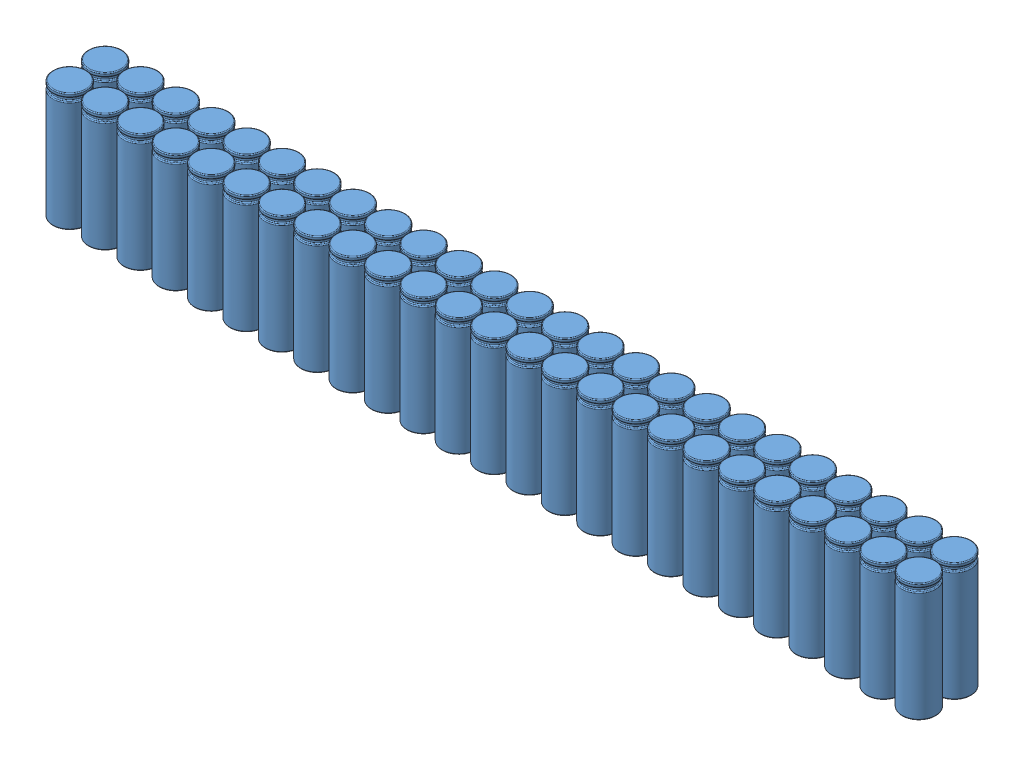
SolidWorks assembly 25x2, configuration Default. Lengths in mm.
Overall size (486.5 65.2 38).
50 component instances, 1 part files, 1 mates.
Components (placement in the parent):
- 18650 NN-1: 18650 NN [Default] at origin size (18.5 65.2 18.5)
- 18650 NN-2: 18650 NN [Default] at (0 0 -19.5) size (18.5 65.2 18.5)
- 18650 NN-3: 18650 NN [Default] at (19.5 0 0) size (18.5 65.2 18.5)
- 18650 NN-4: 18650 NN [Default] at (19.5 0 -19.5) size (18.5 65.2 18.5)
- 18650 NN-5: 18650 NN [Default] at (39 0 0) size (18.5 65.2 18.5)
- 18650 NN-6: 18650 NN [Default] at (39 0 -19.5) size (18.5 65.2 18.5)
- 18650 NN-7: 18650 NN [Default] at (58.5 0 0) size (18.5 65.2 18.5)
- 18650 NN-8: 18650 NN [Default] at (58.5 0 -19.5) size (18.5 65.2 18.5)
- 18650 NN-9: 18650 NN [Default] at (78 0 0) size (18.5 65.2 18.5)
- 18650 NN-10: 18650 NN [Default] at (78 0 -19.5) size (18.5 65.2 18.5)
- 18650 NN-11: 18650 NN [Default] at (97.5 0 0) size (18.5 65.2 18.5)
- 18650 NN-12: 18650 NN [Default] at (97.5 0 -19.5) size (18.5 65.2 18.5)
- 18650 NN-13: 18650 NN [Default] at (117 0 0) size (18.5 65.2 18.5)
- 18650 NN-14: 18650 NN [Default] at (117 0 -19.5) size (18.5 65.2 18.5)
- 18650 NN-15: 18650 NN [Default] at (136.5 0 0) size (18.5 65.2 18.5)
- 18650 NN-16: 18650 NN [Default] at (136.5 0 -19.5) size (18.5 65.2 18.5)
- 18650 NN-17: 18650 NN [Default] at (156 0 0) size (18.5 65.2 18.5)
- 18650 NN-18: 18650 NN [Default] at (156 0 -19.5) size (18.5 65.2 18.5)
- 18650 NN-19: 18650 NN [Default] at (175.5 0 0) size (18.5 65.2 18.5)
- 18650 NN-20: 18650 NN [Default] at (175.5 0 -19.5) size (18.5 65.2 18.5)
- 18650 NN-21: 18650 NN [Default] at (195 0 0) size (18.5 65.2 18.5)
- 18650 NN-22: 18650 NN [Default] at (195 0 -19.5) size (18.5 65.2 18.5)
- 18650 NN-23: 18650 NN [Default] at (214.5 0 0) size (18.5 65.2 18.5)
- 18650 NN-24: 18650 NN [Default] at (214.5 0 -19.5) size (18.5 65.2 18.5)
- 18650 NN-25: 18650 NN [Default] at (234 0 0) size (18.5 65.2 18.5)
- 18650 NN-26: 18650 NN [Default] at (234 0 -19.5) size (18.5 65.2 18.5)
- 18650 NN-27: 18650 NN [Default] at (253.5 0 0) size (18.5 65.2 18.5)
- 18650 NN-28: 18650 NN [Default] at (253.5 0 -19.5) size (18.5 65.2 18.5)
- 18650 NN-29: 18650 NN [Default] at (273 0 0) size (18.5 65.2 18.5)
- 18650 NN-30: 18650 NN [Default] at (273 0 -19.5) size (18.5 65.2 18.5)
- 18650 NN-31: 18650 NN [Default] at (292.5 0 0) size (18.5 65.2 18.5)
- 18650 NN-32: 18650 NN [Default] at (292.5 0 -19.5) size (18.5 65.2 18.5)
- 18650 NN-33: 18650 NN [Default] at (312 0 0) size (18.5 65.2 18.5)
- 18650 NN-34: 18650 NN [Default] at (312 0 -19.5) size (18.5 65.2 18.5)
- 18650 NN-35: 18650 NN [Default] at (331.5 0 0) size (18.5 65.2 18.5)
- 18650 NN-36: 18650 NN [Default] at (331.5 0 -19.5) size (18.5 65.2 18.5)
- 18650 NN-37: 18650 NN [Default] at (351 0 0) size (18.5 65.2 18.5)
- 18650 NN-38: 18650 NN [Default] at (351 0 -19.5) size (18.5 65.2 18.5)
- 18650 NN-39: 18650 NN [Default] at (370.5 0 0) size (18.5 65.2 18.5)
- 18650 NN-40: 18650 NN [Default] at (370.5 0 -19.5) size (18.5 65.2 18.5)
- 18650 NN-41: 18650 NN [Default] at (390 0 0) size (18.5 65.2 18.5)
- 18650 NN-42: 18650 NN [Default] at (390 0 -19.5) size (18.5 65.2 18.5)
- 18650 NN-43: 18650 NN [Default] at (409.5 0 0) size (18.5 65.2 18.5)
- 18650 NN-44: 18650 NN [Default] at (409.5 0 -19.5) size (18.5 65.2 18.5)
- 18650 NN-45: 18650 NN [Default] at (429 0 0) size (18.5 65.2 18.5)
- 18650 NN-46: 18650 NN [Default] at (429 0 -19.5) size (18.5 65.2 18.5)
- 18650 NN-47: 18650 NN [Default] at (448.5 0 0) size (18.5 65.2 18.5)
- 18650 NN-48: 18650 NN [Default] at (448.5 0 -19.5) size (18.5 65.2 18.5)
- 18650 NN-49: 18650 NN [Default] at (468 0 0) size (18.5 65.2 18.5)
- 18650 NN-50: 18650 NN [Default] at (468 0 -19.5) size (18.5 65.2 18.5)
Mates (geometry in assembly coordinates):
- Coincident1: coordinate: point of assembly; point of 18650 NN-1; point of assembly
